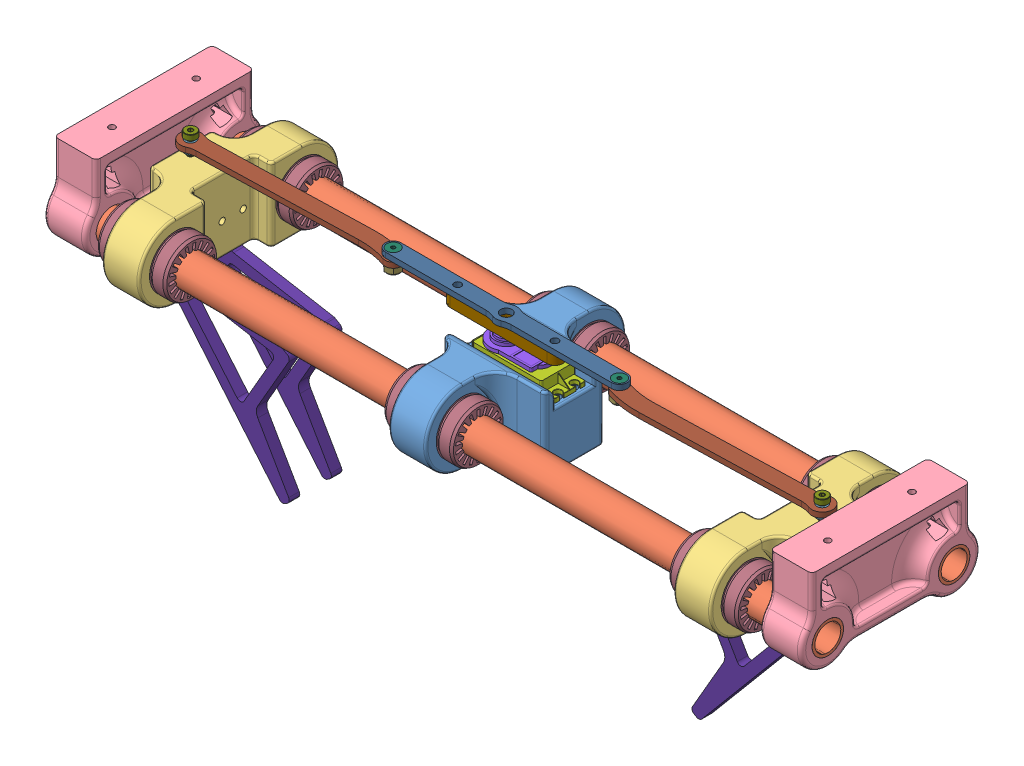
SolidWorks assembly linear linkage claw assembly, configuration Default. Lengths in mm.
Overall size (457.23 154.41 120.65).
33 component instances, 17 part files, 64 mates.
Components (placement in the parent):
- linear linkage claw-1: linear linkage claw [Default] at (148.4376 237.2879 363.6473) size (60.78 44.45 120.65)
- linear linkage claw rod-1: linear linkage claw rod [Default] at (151.2659 237.2879 325.5473) x (1 0 0) z (0 0.07824 0.996935) size (457.2 18.99 18.99)
- linear linkage claw rod-2: linear linkage claw rod [Default] at (151.2659 237.2879 401.7473) x (1 0 0) z (0 -0.901379 0.433032) size (457.2 18.99 18.99)
- linear linkage claw claw1-2: linear linkage claw claw1 [Default] at (320.2901 237.2879 363.6473) size (35.56 44.45 120.65)
- linear linkage claw claw1-3: linear linkage claw claw1 [Default] at (-24.5149 237.2879 363.6473) x (-1 0 0) z (0 0 -1) size (35.56 44.45 120.65)
- linear linkage claw mount-1: linear linkage claw mount [Default] at (367.1659 237.2879 363.6473) x (1 0 0) z (0 0 -1) size (25.43 53.98 107.95)
- linear linkage claw mount-2: linear linkage claw mount [Default] at (-64.6341 237.2879 363.6473) x (1 0 0) z (0 0 -1) size (25.43 53.98 107.95)
- 11886-1: 11886 [Default] at (159.5651 224.7014 361.475) x (0 0 1) z (-1 0 0) size (21 45.43 55.5)
  - 11886_bottom-1: 11886_bottom [Default] at (2.2223 -4.2785 0.9275) size (21 2.43 41.5)
  - 11886_middle-1: 11886_middle [Default] at (2.2223 -1.8785 0.9275) size (21 25.7 42.9)
  - 11886_upper-1: 11886_upper [Default] at (6.1473 23.8215 -5.3225) size (21 8.72 55.5)
  - 11886_top-1: 11886_top [Default] at (2.2223 32.5215 0.7275) size (20 8.6 36.5)
- 525118.step-1: 525118.step [Default] at (147.8876 268.8709 363.6973) x (1 0 0.000262) z (0.000262 0 -1) size (68.2 6.35 9.53)
- linear linkage center linkage-1: linear linkage center linkage [Default] at (147.8876 268.8709 363.6973) x (-1 0 -0.000262) z (0.000262 0 -1) size (146.05 3.17 12.7)
- linear linkage outer linkage-1: linear linkage outer linkage [Default] at (18.5063 264.4259 363.6633) x (1 0 0.000262) z (-0.000262 0 1) size (133.35 3.17 13.96)
- linear linkage outer linkage-2: linear linkage outer linkage [Default] at (277.2688 264.4259 363.6812) x (-1 0 0.000556) z (-0.000556 0 -1) size (133.35 3.17 13.96)
- 90631A007_Low-Strength Steel Nylon-Insert Locknut-1: 90631A007_Low-Strength Steel Nylon-Insert Locknut [90631A007] at (216.1501 264.4259 363.7152) x (-0.837169 0 -0.546944) z (-0.546944 0 0.837169) size (7.94 4.48 9.17)
- 90631A007_Low-Strength Steel Nylon-Insert Locknut-2: 90631A007_Low-Strength Steel Nylon-Insert Locknut [90631A007] at (79.6251 264.4259 363.6794) x (-0.97479 0 -0.223125) z (-0.223125 0 0.97479) size (7.94 4.48 9.17)
- 2570K13_Dust-Resistant Linear Sleeve Bearing-1: 2570K13_Dust-Resistant Linear Sleeve Bearing [2570K13] at (320.2774 237.2879 401.7473) x (0 0 -1) z (-1 0 0) size (31.75 31.75 41.27)
- 2570K13_Dust-Resistant Linear Sleeve Bearing-2: 2570K13_Dust-Resistant Linear Sleeve Bearing [2570K13] at (320.2774 237.2879 325.5473) x (0 0 1) z (-1 0 0) size (31.75 31.75 41.27)
- 2570K13_Dust-Resistant Linear Sleeve Bearing-3: 2570K13_Dust-Resistant Linear Sleeve Bearing [2570K13] at (148.4249 237.2879 325.5473) x (0 0 1) z (-1 0 0) size (31.75 31.75 41.27)
- 2570K13_Dust-Resistant Linear Sleeve Bearing-4: 2570K13_Dust-Resistant Linear Sleeve Bearing [2570K13] at (148.4249 237.2879 401.7473) x (0 0 -1) z (-1 0 0) size (31.75 31.75 41.27)
- 2570K13_Dust-Resistant Linear Sleeve Bearing-5: 2570K13_Dust-Resistant Linear Sleeve Bearing [2570K13] at (-24.5022 237.2879 325.5473) x (0 0.924225 0.381849) z (1 0 0) size (31.75 31.75 41.27)
- 2570K13_Dust-Resistant Linear Sleeve Bearing-6: 2570K13_Dust-Resistant Linear Sleeve Bearing [2570K13] at (-24.5022 237.2879 401.7473) x (0 -0.225479 0.974248) z (1 0 0) size (31.75 31.75 41.27)
- 6391K927_Oil-Embedded Bronze Sleeve Bearing-1: 6391K927_Oil-Embedded Bronze Sleeve Bearing [6391K927] at (-42.6124 264.4259 363.6473) x (-0.592239 0 -0.805762) z (0 1 0) size (6.4 6.4 6.35)
- 6391K927_Oil-Embedded Bronze Sleeve Bearing-2: 6391K927_Oil-Embedded Bronze Sleeve Bearing [6391K927] at (338.3876 264.4259 363.6473) x (0.936492 0 0.350689) z (0 1 0) size (6.4 6.4 6.35)
- 91253A148_Black-Oxide Alloy Steel Hex Drive Flat Head Screw-1: 91253A148_Black-Oxide Alloy Steel Hex Drive Flat Head Screw [91253A148] at (216.1501 272.0459 363.7152) x (0.036712 0 -0.999326) z (0 1 0) size (7.8 7.8 13.08)
- 91253A148_Black-Oxide Alloy Steel Hex Drive Flat Head Screw-3: 91253A148_Black-Oxide Alloy Steel Hex Drive Flat Head Screw [91253A148] at (79.6251 272.0459 363.6794) x (0.306279 0 0.951942) z (0 1 0) size (7.8 7.8 13.08)
- 90325A163_18-8 Stainless Steel Precision Shoulder Screw-1: 90325A163_18-8 Stainless Steel Precision Shoulder Screw [90325A163] at (338.3876 272.2129 363.6473) x (1 0 0) z (0 1 0) size (7.14 7.14 22.71)
- 90325A163_18-8 Stainless Steel Precision Shoulder Screw-2: 90325A163_18-8 Stainless Steel Precision Shoulder Screw [90325A163] at (-42.6124 272.2129 363.6473) x (0.679574 0 -0.733607) z (0 1 0) size (7.14 7.14 22.71)
- linear linkage claw piece-1: linear linkage claw piece [Default] at (19.3001 161.0879 376.3473) size (70.63 119.48 6.35)
- linear linkage claw piece-2: linear linkage claw piece [Default] at (19.3001 161.0879 350.9473) size (70.63 119.48 6.35)
- linear linkage claw piece-3: linear linkage claw piece [Default] at (276.4751 161.0879 363.6473) x (-1 0 0) z (0 0 -1) size (70.63 119.48 6.35)
Mates (geometry in assembly coordinates):
- Concentric1: concentric anti-aligned: cylinder of linear linkage claw-1 through (83.2963 237.2879 325.5473) axis (1 0 0) radius 15.875; cylinder of linear linkage claw rod-1 through (-77.3341 237.2879 325.5473) axis (-1 0 0) radius 9.4958
- Concentric2: concentric anti-aligned: cylinder of linear linkage claw-1 through (83.2963 237.2879 401.7473) axis (1 0 0) radius 15.875; cylinder of linear linkage claw rod-2 through (-77.3341 237.2879 401.7473) axis (-1 0 0) radius 9.4958
- Coincident1: coincident aligned: plane of linear linkage claw rod-1 through (379.8659 237.2879 325.5473) normal (1 0 0); plane of linear linkage claw rod-2 through (379.8659 237.2879 401.7473) normal (1 0 0)
- Concentric3: concentric anti-aligned: circle of linear linkage claw rod-2; cylinder of linear linkage claw claw1-2 through (264.2763 237.2879 401.7473) axis (1 0 0) radius 22.225
- Concentric4: concentric anti-aligned: cylinder of linear linkage claw rod-1 through (-77.3341 237.2879 325.5473) axis (-1 0 0) radius 9.4958; cylinder of linear linkage claw claw1-2 through (264.2763 237.2879 325.5473) axis (1 0 0) radius 22.225
- Concentric11: concentric aligned: cylinder of linear linkage claw rod-2 through (-77.3341 237.2879 401.7473) axis (-1 0 0) radius 9.4958; cylinder of linear linkage claw mount-1 through (379.8659 237.2879 401.7473) axis (-1 0 0) radius 9.525
- Concentric12: concentric aligned: cylinder of linear linkage claw rod-1 through (-77.3341 237.2879 325.5473) axis (-1 0 0) radius 9.4958; cylinder of linear linkage claw mount-1 through (379.8659 237.2879 325.5473) axis (-1 0 0) radius 9.525
- Coincident2: coincident aligned: plane of linear linkage claw rod-2 through (379.8659 237.2879 401.7473) normal (1 0 0); plane of linear linkage claw mount-1 through (379.8659 237.2879 325.5473) normal (1 0 0)
- Concentric13: concentric aligned: cylinder of linear linkage claw rod-2 through (-77.3341 237.2879 401.7473) axis (-1 0 0) radius 9.4958; cylinder of linear linkage claw mount-2 through (-51.9341 237.2879 401.7473) axis (-1 0 0) radius 9.525
- Concentric14: concentric aligned: cylinder of linear linkage claw rod-1 through (-77.3341 237.2879 325.5473) axis (-1 0 0) radius 9.4958; cylinder of linear linkage claw mount-2 through (-51.9341 237.2879 325.5473) axis (-1 0 0) radius 9.525
- Coincident3: coincident aligned: plane of linear linkage claw rod-1 through (-77.3341 237.2879 325.5473) normal (-1 0 0); plane of linear linkage claw mount-2 through (-77.3341 237.2879 325.5473) normal (-1 0 0)
- Concentric15: concentric anti-aligned: circle of linear linkage claw-1; circle of 11886-1/11886_upper-1
- Parallel1: parallel anti-aligned: plane of linear linkage claw-1 through (180.6076 259.5129 351.9773) normal (0 0 1); plane of 11886-1/11886_middle-1 through (137.8876 248.5229 353.1973) normal (0 0 -1)
- Coincident5: coincident anti-aligned: plane of linear linkage claw-1 through (148.4376 248.5229 363.6473) normal (0 1 0); plane of 11886-1/11886_upper-1 through (179.3876 248.5229 353.1973) normal (0 -1 0)
- Concentric19: concentric anti-aligned: circle of 11886-1/11886_top-1; circle of 525118.step-1
- Coincident10: coincident anti-aligned: plane of 11886-1/11886_top-1 through (147.8876 265.8229 357.2859) normal (0 1 0); plane of 525118.step-1 through (147.8876 265.8229 363.6973) normal (0 -1 0)
- Concentric20: concentric aligned: circle of 525118.step-1; circle of linear linkage center linkage-1
- Coincident11: coincident anti-aligned: plane of 525118.step-1 through (177.2246 268.8709 363.705) normal (0 1 0); plane of linear linkage center linkage-1 through (147.8876 268.8709 363.6973) normal (0 -1 0)
- Coincident12: coincident aligned: plane of 525118.step-1 through (118.5518 262.5209 358.9271) normal (0.000262 0 -1); plane of linear linkage center linkage-1 through (147.8888 272.0459 358.9348) normal (0.000262 0 -1)
- Concentric21: concentric anti-aligned: circle of linear linkage center linkage-1; circle of linear linkage outer linkage-1
- Distance1: distance = 1.27 mm anti-aligned: plane of linear linkage outer linkage-1 through (18.5063 267.6009 363.6633) normal (0 1 0); plane of linear linkage center linkage-1 through (147.8876 268.8709 363.6973) normal (0 -1 0)
- Concentric23: concentric aligned: circle of linear linkage center linkage-1; circle of linear linkage outer linkage-2
- Distance2: distance = 1.27 mm anti-aligned: plane of linear linkage outer linkage-2 through (277.2688 267.6009 363.6812) normal (0 1 0); plane of linear linkage center linkage-1 through (147.8876 268.8709 363.6973) normal (0 -1 0)
- Concentric26: concentric aligned: cylinder of linear linkage claw claw1-2 through (338.3876 259.5129 363.6473) axis (0 -1 0) radius 1.905; cylinder of linear linkage outer linkage-2 through (338.3876 267.6009 363.6473) axis (0 -1 0) radius 3.175
- Coincident19: coincident anti-aligned: plane of linear linkage outer linkage-2 through (277.2688 264.4259 363.6812) normal (0 -1 0); plane of 90631A007_Low-Strength Steel Nylon-Insert Locknut-1 through (223.2323 264.4259 360.1311) normal (0 1 0)
- Concentric27: concentric anti-aligned: cylinder of linear linkage outer linkage-2 through (216.1501 267.6009 363.7152) axis (0 -1 0) radius 1.905; circle of 90631A007_Low-Strength Steel Nylon-Insert Locknut-1
- Concentric28: concentric anti-aligned: circle of 90631A007_Low-Strength Steel Nylon-Insert Locknut-2; cylinder of linear linkage outer linkage-1 through (79.6251 267.6009 363.6794) axis (0 -1 0) radius 1.905
- Coincident20: coincident anti-aligned: plane of linear linkage outer linkage-1 through (18.5063 264.4259 363.6633) normal (0 -1 0); plane of 90631A007_Low-Strength Steel Nylon-Insert Locknut-2 through (85.0276 264.4259 357.8641) normal (0 1 0)
- Concentric29: concentric aligned: circle of linear linkage claw claw1-2; circle of 2570K13_Dust-Resistant Linear Sleeve Bearing-1
- Coincident24: coincident aligned: plane of linear linkage claw claw1-2 through (331.4026 259.5129 363.6473) normal (1 0 0); plane of 2570K13_Dust-Resistant Linear Sleeve Bearing-1 through (331.4026 222.34 401.7473) normal (1 0 0)
- Concentric30: concentric anti-aligned: circle of linear linkage claw claw1-2; circle of 2570K13_Dust-Resistant Linear Sleeve Bearing-2
- Coincident26: coincident aligned: plane of linear linkage claw claw1-2 through (331.4026 259.5129 363.6473) normal (1 0 0); plane of 2570K13_Dust-Resistant Linear Sleeve Bearing-2 through (331.4026 252.2358 325.5473) normal (1 0 0)
- Concentric31: concentric anti-aligned: circle of linear linkage claw-1; circle of 2570K13_Dust-Resistant Linear Sleeve Bearing-3
- Coincident28: coincident aligned: plane of linear linkage claw-1 through (159.5501 259.5129 303.3223) normal (1 0 0); plane of 2570K13_Dust-Resistant Linear Sleeve Bearing-3 through (159.5501 252.2358 325.5473) normal (1 0 0)
- Concentric32: concentric aligned: circle of linear linkage claw-1; circle of 2570K13_Dust-Resistant Linear Sleeve Bearing-4
- Coincident30: coincident aligned: plane of linear linkage claw-1 through (159.5501 259.5129 381.6673) normal (1 0 0); plane of 2570K13_Dust-Resistant Linear Sleeve Bearing-4 through (159.5501 222.34 401.7473) normal (1 0 0)
- Concentric33: concentric anti-aligned: circle of linear linkage claw claw1-3; circle of 2570K13_Dust-Resistant Linear Sleeve Bearing-6
- Coincident32: coincident aligned: plane of linear linkage claw claw1-3 through (-35.6274 259.5129 363.6473) normal (-1 0 0); plane of 2570K13_Dust-Resistant Linear Sleeve Bearing-6 through (-35.6274 222.7249 398.3768) normal (-1 0 0)
- Coincident33: coincident aligned: plane of linear linkage claw claw1-3 through (-35.6274 259.5129 363.6473) normal (-1 0 0); plane of 2570K13_Dust-Resistant Linear Sleeve Bearing-5 through (-35.6274 231.5801 339.3625) normal (-1 0 0)
- Concentric34: concentric aligned: circle of linear linkage claw claw1-3; circle of 2570K13_Dust-Resistant Linear Sleeve Bearing-5
- Concentric35: concentric aligned: circle of linear linkage outer linkage-1; circle of 6391K927_Oil-Embedded Bronze Sleeve Bearing-1
- Coincident35: coincident aligned: plane of linear linkage outer linkage-1 through (18.5063 267.6009 363.6633) normal (0 1 0); plane of 6391K927_Oil-Embedded Bronze Sleeve Bearing-1 through (-42.6124 267.6009 363.6473) normal (0 1 0)
- Concentric36: concentric aligned: circle of linear linkage outer linkage-2; circle of 6391K927_Oil-Embedded Bronze Sleeve Bearing-2
- Coincident36: coincident aligned: plane of linear linkage outer linkage-2 through (277.2688 267.6009 363.6812) normal (0 1 0); plane of 6391K927_Oil-Embedded Bronze Sleeve Bearing-2 through (338.3876 267.6009 363.6473) normal (0 1 0)
- Concentric40: concentric anti-aligned: cylinder of linear linkage center linkage-1 through (216.1501 272.0459 363.7152) axis (0 -1 0) radius 1.905; circle of 91253A148_Black-Oxide Alloy Steel Hex Drive Flat Head Screw-1
- Coincident40: coincident aligned: plane of linear linkage center linkage-1 through (147.8876 272.0459 363.6973) normal (0 1 0); plane of 91253A148_Black-Oxide Alloy Steel Hex Drive Flat Head Screw-1 through (217.9015 272.0459 363.7795) normal (0 1 0)
- Coincident42: coincident aligned: plane of linear linkage center linkage-1 through (147.8876 272.0459 363.6973) normal (0 1 0); plane of 91253A148_Black-Oxide Alloy Steel Hex Drive Flat Head Screw-3 through (77.9567 272.0459 364.2162) normal (0 1 0)
- Concentric41: concentric anti-aligned: cylinder of linear linkage center linkage-1 through (79.6251 272.0459 363.6794) axis (0 -1 0) radius 1.905; circle of 91253A148_Black-Oxide Alloy Steel Hex Drive Flat Head Screw-3
- Concentric43: concentric anti-aligned: circle of linear linkage claw claw1-2; circle of 90325A163_18-8 Stainless Steel Precision Shoulder Screw-1
- Coincident44: coincident anti-aligned: plane of linear linkage claw claw1-2 through (320.2901 259.5129 363.6473) normal (0 1 0); circle of 90325A163_18-8 Stainless Steel Precision Shoulder Screw-1
- Concentric44: concentric aligned: cylinder of linear linkage claw rod-1 through (-77.3341 237.2879 325.5473) axis (-1 0 0) radius 9.4958; cylinder of linear linkage claw claw1-3 through (31.4989 237.2879 325.5473) axis (-1 0 0) radius 22.225
- Concentric45: concentric aligned: cylinder of linear linkage claw rod-2 through (-77.3341 237.2879 401.7473) axis (-1 0 0) radius 9.4958; cylinder of linear linkage claw claw1-3 through (31.4989 237.2879 401.7473) axis (-1 0 0) radius 22.225
- Concentric46: concentric aligned: circle of linear linkage claw claw1-3; circle of linear linkage outer linkage-1
- Concentric47: concentric anti-aligned: circle of linear linkage claw claw1-3; circle of 90325A163_18-8 Stainless Steel Precision Shoulder Screw-2
- Coincident45: coincident anti-aligned: plane of linear linkage claw claw1-3 through (-24.5149 259.5129 363.6473) normal (0 1 0); circle of 90325A163_18-8 Stainless Steel Precision Shoulder Screw-2
- Concentric48: concentric aligned: circle of linear linkage claw claw1-3; circle of linear linkage claw piece-1
- Parallel2: parallel anti-aligned: plane of linear linkage claw claw1-3 through (-28.0709 240.4629 379.7763) normal (0 0 -1); plane of linear linkage claw piece-1 through (19.3001 161.0879 379.5223) normal (0 0 1)
- Symmetric1: symmetric aligned: plane of linear linkage claw claw1-3 through (-33.0874 237.2879 363.6473) normal (1 0 0); plane of linear linkage claw piece-1 through (-37.8499 240.4629 379.5223) normal (-1 0 0); plane of linear linkage claw piece-1 through (-28.3249 240.4629 379.5223) normal (1 0 0)
- Concentric49: concentric aligned: circle of linear linkage claw claw1-3; cylinder of linear linkage claw piece-2 through (-43.2381 234.1129 350.9473) axis (1 0 0) radius 1.905
- Parallel3: parallel anti-aligned: plane of linear linkage claw claw1-3 through (-28.0709 240.4629 347.5183) normal (0 0 1); plane of linear linkage claw piece-2 through (19.3001 161.0879 347.7723) normal (0 0 -1)
- Symmetric2: symmetric aligned: plane of linear linkage claw claw1-3 through (-33.0874 237.2879 363.6473) normal (1 0 0); plane of linear linkage claw piece-2 through (-28.3249 240.4629 354.1223) normal (1 0 0); plane of linear linkage claw piece-2 through (-37.8499 240.4629 354.1223) normal (-1 0 0)
- Symmetric3: symmetric aligned: plane of linear linkage claw claw1-2 through (328.8626 237.2879 363.6473) normal (-1 0 0); plane of linear linkage claw piece-3 through (333.6251 240.4629 360.4723) normal (1 0 0); plane of linear linkage claw piece-3 through (324.1001 240.4629 360.4723) normal (-1 0 0)
- Concentric50: concentric aligned: circle of linear linkage claw claw1-2; cylinder of linear linkage claw piece-3 through (339.0132 234.1129 363.6473) axis (-1 0 0) radius 1.905
- Parallel4: parallel anti-aligned: plane of linear linkage claw claw1-2 through (323.8461 240.4629 360.2183) normal (0 0 1); plane of linear linkage claw piece-3 through (276.4751 161.0879 360.4723) normal (0 0 -1)
